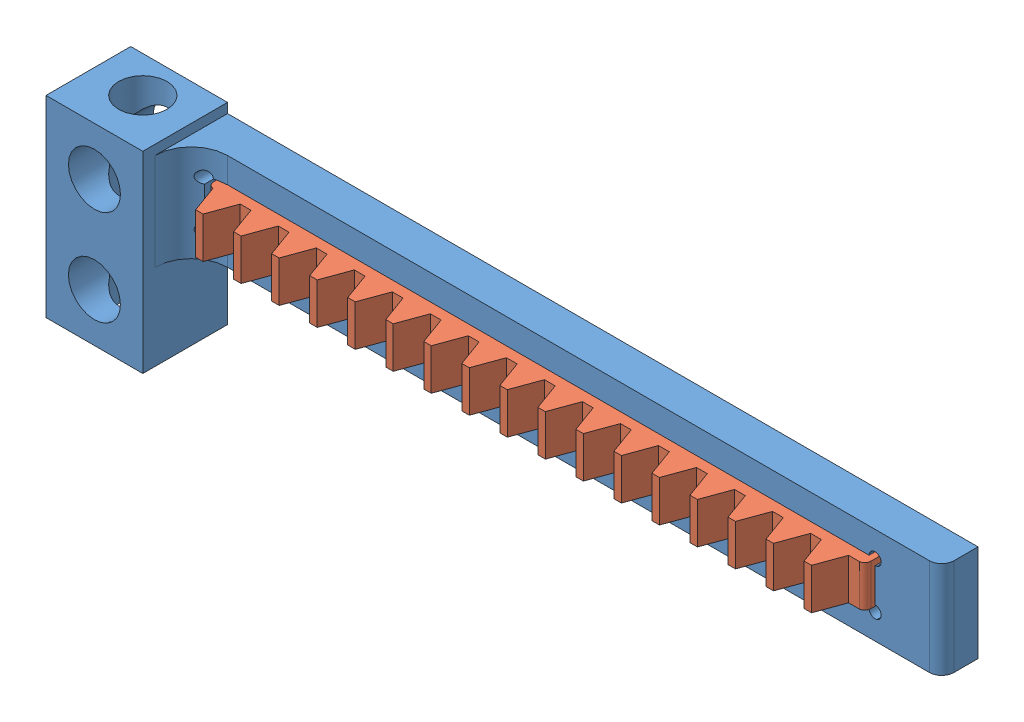
SolidWorks assembly rack gear, configuration Standard. Lengths in mm.
Overall size (70 15.9 7).
2 component instances, 2 part files, 18 mates.
Components (placement in the parent):
- rack gear body-1: rack gear body [Standard] at (-48.626 8.3754 -1.5) size (70 15.9 7)
- rack spur-3: rack spur [ISO - Rack-spur - rectangular 1M 20PA 3.4FW 4.7PH 54.3L---SAll] at (-73.826 6.4754 -3) x (1 0 0) z (0 -1 0) size (54.3 5.7 3.4)
Mates (geometry in assembly coordinates):
- Deckungsgleich2: coincident aligned: plane of rack gear body-1 through (-48.626 8.3754 -3) normal (0 0 -1); plane of ? through (-70.426 6.4754 -3) normal (0 0 -1)
- Deckungsgleich3: coincident anti-aligned: plane of rack gear body-1 through (-74.126 6.4754 0) normal (0 1 0); plane of ? through (-39.5414 6.4754 -3) normal (0 -1 0)
- Deckungsgleich4: coincident anti-aligned: plane of rack gear body-1 through (-19.126 10.2754 0) normal (-1 0 0); plane of ? through (-19.126 6.4754 2.4) normal (1 0 0)
- Deckungsgleich5: coincident anti-aligned: plane of ? through (-38.0414 6.4754 -3) normal (0 -1 0); plane of ? through (-59.4879 6.4754 3.2034) normal (0 1 0)
- Deckungsgleich6: coincident anti-aligned: plane of ? through (-59.4879 3.0754 3.2034) normal (0 -1 0); plane of ? through (-69.5661 3.0754 2.4591) normal (0 1 0)
- Deckungsgleich7: coincident aligned: plane of ? through (-70.426 6.4754 -3) normal (0 0 -1); plane of ? through (-70.426 6.4754 -3) normal (0 0 -1)
- Deckungsgleich8: coincident aligned: plane of ? through (-70.426 6.4754 2.4) normal (-1 0 0); plane of ? through (-70.426 6.4754 -3) normal (-1 0 0)
- Deckungsgleich9: coincident anti-aligned: plane of ? through (-39.5414 6.4754 -3) normal (0 -1 0); plane of ? through (-70.426 6.4754 2.5) normal (0 1 0)
- Deckungsgleich10: coincident anti-aligned: plane of ? through (-70.426 3.0754 2.5) normal (0 -1 0); plane of ? through (-60.6044 3.0754 2.2855) normal (0 1 0)
- Abstand1: distance = 0.3 mm anti-aligned: plane of rack gear body-1 through (-74.126 10.2754 0) normal (1 0 0); plane of rack spur-3 through (-73.826 9.8754 -3) normal (-1 0 0)
- Deckungsgleich14: coincident anti-aligned: plane of rack gear body-1 through (-74.126 6.4754 0) normal (0 1 0); plane of rack spur-3 through (-73.826 6.4754 2.7) normal (0 -1 0)
- Deckungsgleich16: coincident aligned: plane of rack gear body-1 through (-48.626 8.3754 -3) normal (0 0 -1); plane of rack spur-3 through (-73.826 9.8754 -3) normal (0 0 -1)
- Deckungsgleich17: coincident anti-aligned: plane of rack gear body-1 through (-74.126 6.4754 0) normal (0 1 0); plane of rack spur-3 through (-73.826 6.4754 2.7) normal (0 -1 0)
- Deckungsgleich18: coincident aligned: plane of rack gear body-1 through (-48.626 8.3754 -3) normal (0 0 -1); plane of rack spur-3 through (-73.826 9.8754 -3) normal (0 0 -1)
- Abstand2: distance = 0.3 mm anti-aligned: plane of rack spur-3 through (-73.826 9.8754 -3) normal (-1 0 0); plane of rack gear body-1 through (-74.126 10.2754 0) normal (1 0 0)
- Deckungsgleich19: coincident anti-aligned: plane of rack gear body-1 through (-74.126 6.4754 0) normal (0 1 0); plane of rack spur-3 through (-72.637 6.4754 2.7) normal (0 -1 0)
- Deckungsgleich20: coincident aligned: plane of rack gear body-1 through (-48.626 8.3754 -3) normal (0 0 -1); plane of rack spur-3 through (-72.637 9.8754 -3) normal (0 0 -1)
- Abstand3: distance = 0.3 mm anti-aligned: plane of rack spur-3 through (-73.826 9.8754 -3) normal (-1 0 0); plane of rack gear body-1 through (-74.126 10.2754 0) normal (1 0 0)
